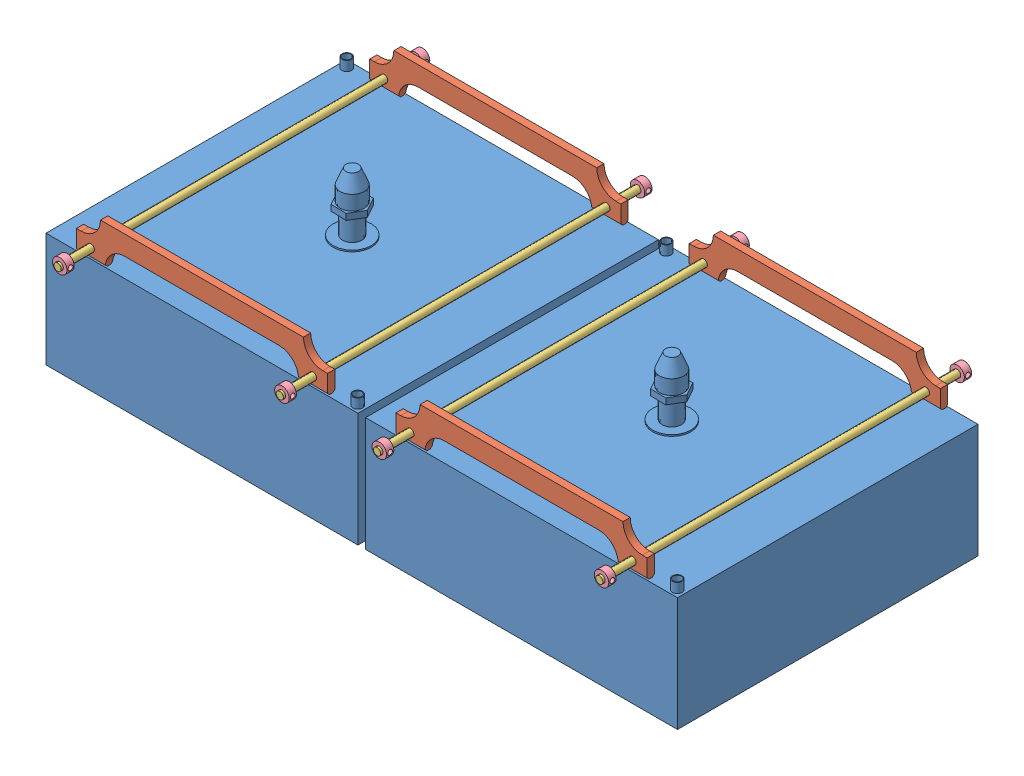
SolidWorks assembly 100-UltraSoundSourceNew, configuration Upside-down. Lengths in mm.
Overall size (830 228.1 482.6).
19 component instances, 4 part files, 18 mates.
Components (placement in the parent):
- 101-UltraSoundBox-1: 101-UltraSoundBox [Default] at (-210 0 0)
- 101-UltraSoundBox-2: 101-UltraSoundBox [Default] at (210 0 0)
- 102-RodHolder-1: 102-RodHolder [Default] at (-210 0 197.5)
- 102-RodHolder-4: 102-RodHolder [Default] at (210 0 197.5)
- 103-RodYokes-1: 103-RodYokes [Default] at origin
- 103-RodYokes-3: 103-RodYokes [Default] at (292.1 0 0)
- 103-RodYokes-4: 103-RodYokes [Default] at (712.1 0 0)
- 103-RodYokes-2: 103-RodYokes [Default] at (420 0 0)
- 102-RodHolder-2: 102-RodHolder [Default] at (-210 0 -188.0212)
- 102-RodHolder-3: 102-RodHolder [Default] at (210 0 -188.0212)
- 004-ShaftCollar_Mcmaster-9943K18-1: 004-ShaftCollar_Mcmaster-9943K18 [Default] at origin (hidden)
- 004-ShaftCollar_Mcmaster-9943K18-2: 004-ShaftCollar_Mcmaster-9943K18 [Default] at (0 0 233.68)
- 004-ShaftCollar_Mcmaster-9943K18-6: 004-ShaftCollar_Mcmaster-9943K18 [Default] at (0 0 -233.68)
- 004-ShaftCollar_Mcmaster-9943K18-7: 004-ShaftCollar_Mcmaster-9943K18 [Default] at (292.1 0 -233.68)
- 004-ShaftCollar_Mcmaster-9943K18-3: 004-ShaftCollar_Mcmaster-9943K18 [Default] at (292.1 0 233.68)
- 004-ShaftCollar_Mcmaster-9943K18-5: 004-ShaftCollar_Mcmaster-9943K18 [Default] at (420.0652 0 233.68)
- 004-ShaftCollar_Mcmaster-9943K18-9: 004-ShaftCollar_Mcmaster-9943K18 [Default] at (420.0652 0 -233.68)
- 004-ShaftCollar_Mcmaster-9943K18-4: 004-ShaftCollar_Mcmaster-9943K18 [Default] at (712.1652 0 233.68)
- 004-ShaftCollar_Mcmaster-9943K18-8: 004-ShaftCollar_Mcmaster-9943K18 [Default] at (712.1652 0 -233.68)
Mates (geometry in assembly coordinates):
- Coincident1: coincident aligned: plane of 101-UltraSoundBox-1 through (-210 0 0) normal (0 0 1); plane of assembly through (0 0 0) normal (0 0 1)
- Coincident2: coincident aligned: plane of 101-UltraSoundBox-1 through (-210 0 0) normal (0 1 0); plane of assembly through (0 0 0) normal (0 1 0)
- Distance1: distance = 5 mm aligned: plane of 101-UltraSoundBox-1 through (-5 150 197.5) normal (1 0 0); plane of assembly through (0 0 0) normal (1 0 0)
- InPlace1: in place: plane of 101-UltraSoundBox-1 through (-415 0 197.5) normal (0 0 1); plane of 102-RodHolder-1; moOrthogonalPlaneRef_w of 101-UltraSoundBox-1; plane of 102-RodHolder-1; moOrthogonalPlaneRef_w of 101-UltraSoundBox-1; plane of 102-RodHolder-1
- Coincident4: coincident aligned: plane of 101-UltraSoundBox-1; plane of 102-RodHolder-1
- Coincident5: coincident aligned: moOrthogonalPlaneRef_w of 101-UltraSoundBox-1 through (-210 0 197.5) axis (0 1 0); plane of 102-RodHolder-1 through (-210 0 197.5) normal (0 1 0)
- Coincident6: coincident anti-aligned: moOrthogonalPlaneRef_w of 101-UltraSoundBox-1 through (-210 0 197.5) axis (-1 0 0); plane of 102-RodHolder-1 through (-210 0 197.5) normal (1 0 0)
- InPlace2: in place: unknown of ?
- Coincident7: coincident aligned: plane of 103-RodYokes-1; plane of assembly
- Coincident8: coincident aligned: plane of ? through (0 0 0) normal (0 1 0)
- Coincident9: coincident anti-aligned: plane of ? through (0 0 0) normal (1 0 0)
- Concentric1: concentric anti-aligned: cylinder of 102-RodHolder-1 through (-63.95 162.7 187.975) axis (0 0 1) radius 4.7625; cylinder of 103-RodYokes-3 through (-63.95 162.7 241.3) axis (0 0 -1) radius 4.7625
- Coincident10: coincident aligned: plane of 103-RodYokes-1 through (-356.05 162.7 241.3) normal (0 0 1); plane of 103-RodYokes-3 through (-63.95 162.7 241.3) normal (0 0 1)
- Parallel1: parallel aligned: plane of 103-RodYokes-1 through (0 0 0) normal (0 1 0); plane of 103-RodYokes-3 through (292.1 0 0) normal (0 1 0)
- InPlace3: in place: unknown of ?
- Coincident11: coincident aligned: plane of 004-ShaftCollar_Mcmaster-9943K18-1; plane of assembly
- Coincident12: coincident aligned: plane of ? through (0 0 0) normal (0 1 0)
- Coincident13: coincident anti-aligned: plane of ? through (0 0 0) normal (1 0 0)
